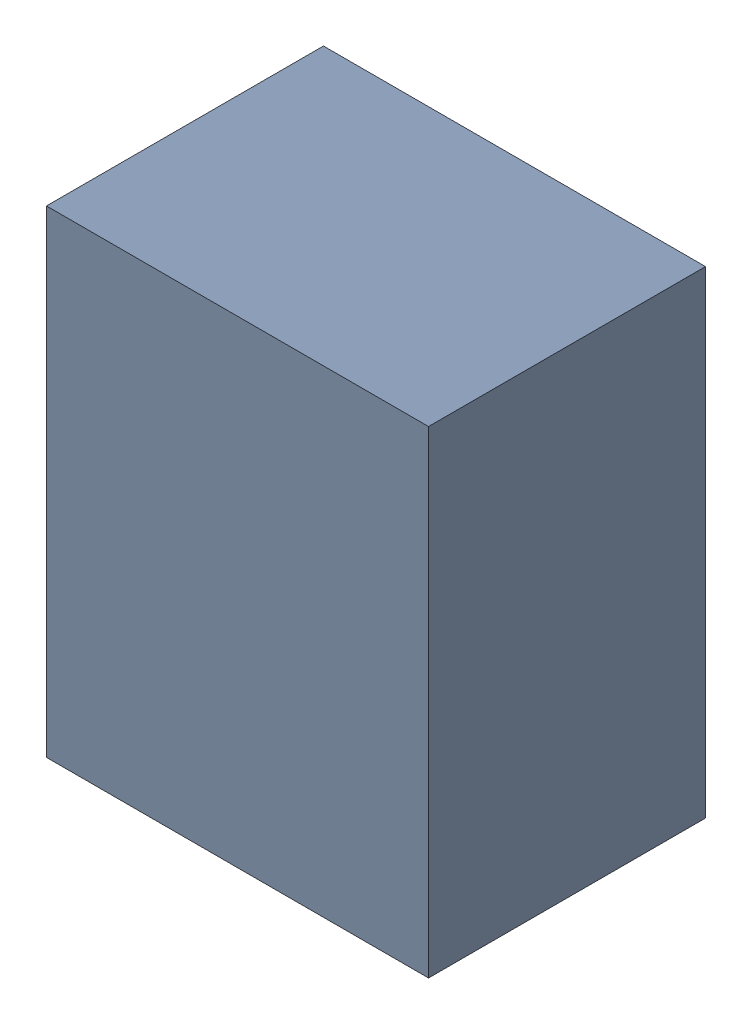
SolidWorks assembly U26, configuration Default. Lengths in mm.
Overall size (0.8 1 0.58).
2 component instances, 1 part files, 0 mates.
Components (placement in the parent):
- 836751984-1: 836751984 [Default] at (133.05 69.15 0.5) size (0.8 1 0.58)
  - Extruded_32-1: Extruded_32 [Default] at origin size (0.8 1 0.58)
